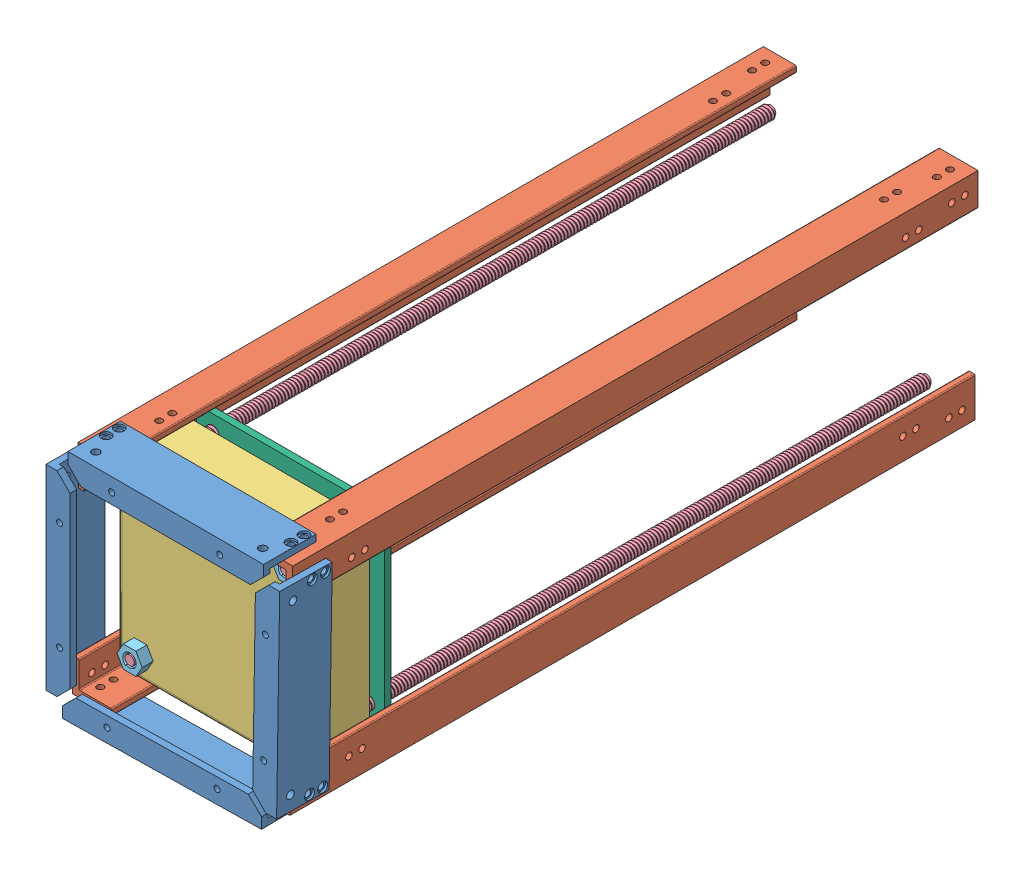
SolidWorks assembly RADIO2, configuration Default. Lengths in mm.
Overall size (103.88 103.99 324.84).
18 component instances, 6 part files, 26 mates.
Components (placement in the parent):
- Top Sipport-9: Top Sipport [Default] at (-70.7593 190.2338 9.9618) x (0 -0.999877 0.015674) z (0 -0.015674 -0.999877) size (89.4 11 24)
- Top Sipport-10: Top Sipport [Default] at (-113.8302 133.6631 11.3482) x (-0.999847 0 0.01749) z (-0.01749 0 -0.999847) size (89.4 11 24)
- Top Sipport-11: Top Sipport [Default] at (-170.4266 177.1068 12.2014) x (0 1 0) z (0 0 -1) size (89.4 11 24)
- Top Sipport-12: Top Sipport [Default] at (-127.1008 233.4379 9.4033) x (1 0 0) z (0 0 -1) size (89.4 11 24)
- Support-6: Support [Default] at (-166.8769 134.5557 -290.4415) x (1 0 0) z (0 1 0) size (18 313 15)
- Support-7: Support [Default] at (-169.6519 229.8882 -293.2396) x (0 -1 0) z (1 0 0) size (18 313 15)
- Support-8: Support [Default] at (-74.309 232.5453 -293.2396) x (-1 0 0) z (0 -1 0) size (18 313 15)
- Support-9: Support [Default] at (-71.6519 137.2129 -291.9167) x (0 1 0) z (-1 0 0) size (18 313 15)
- Top Plate2-2: Top Plate2 [Default] at (-98.3341 162.8515 -14.5967) x (0 -1 0) z (0 0 -1) size (92 92 23)
- Threaded Rod2-1: Threaded Rod2 [Default] at (-85.1519 148.0453 -302.5967) size (6.4 7.01 294.26)
- Nut-1: Nut [Default] at (-85.1519 148.0453 -14.5967) size (11.55 10 5.32)
- Nut-2: Nut [Default] at (-156.1519 219.0453 -14.5967) size (11.55 10 5.32)
- Nut-3: Nut [Default] at (-85.1519 219.0453 -14.5967) size (11.55 10 5.32)
- Nut-4: Nut [Default] at (-156.1519 148.0453 -14.5967) size (11.55 10 5.32)
- Threaded Rod2-2: Threaded Rod2 [Default] at (-156.1519 219.0453 -302.5967) size (6.4 7.01 294.26)
- Threaded Rod2-3: Threaded Rod2 [Default] at (-85.1519 219.0453 -302.5967) size (6.4 7.01 294.26)
- Threaded Rod2-4: Threaded Rod2 [Default] at (-156.1519 148.0453 -302.5967) size (6.4 7.01 294.26)
- Mid Plate-1: Mid Plate [Default] at (-150.0137 193.5688 -50.5967) size (86 86 3)
Mates (geometry in assembly coordinates):
- Coincident83: coincident: circle of Top Sipport-10; circle of Support-6
- Coincident84: coincident: circle of Top Sipport-11; circle of Support-6
- Coincident85: coincident: circle of Top Sipport-12; circle of Support-7
- Coincident87: coincident: circle of Top Sipport-12; circle of Support-7
- Coincident88: coincident: circle of Top Sipport-9; circle of Support-8
- Coincident89: coincident: circle of Top Sipport-12; circle of Support-8
- Coincident90: coincident: circle of Top Sipport-9; circle of Support-9
- Coincident91: coincident: circle of Top Sipport-10; circle of Support-9
- Coincident92: coincident: circle of Support-8; circle of Top Plate2-2
- Parallel9: parallel: line of Top Sipport-11 through (-169.2527 138.8376 -12.4981) axis (0 1 0); line of Top Plate2-2 through (-163.6519 141.5453 -37.5967) axis (0 1 0)
- Parallel10: parallel: line of Support-7 through (-169.6519 232.5453 -312.5967) axis (0 0 1); line of Top Plate2-2 through (-78.6519 140.5453 -37.5967) axis (0 0 1)
- Coincident95: coincident: circle of Top Plate2-2; circle of Nut-1
- Concentric10: concentric: circle of Top Plate2-2; circle of Threaded Rod2-1
- Coincident96: coincident: plane of Threaded Rod2-1 through (-85.1519 148.0453 -9.5967) normal (0 0 1); plane of Nut-1 through (-85.1519 148.0453 -9.5967) normal (0 0 1)
- Coincident97: coincident: circle of Top Plate2-2; circle of Nut-4
- Coincident98: coincident: circle of Top Plate2-2; circle of Nut-3
- Coincident99: coincident: circle of Top Plate2-2; circle of Nut-2
- Concentric11: concentric: circle of Top Plate2-2; circle of Threaded Rod2-2
- Coincident100: coincident: plane of Nut-2 through (-156.1519 219.0453 -9.5967) normal (0 0 1); plane of Threaded Rod2-2 through (-156.1519 219.0453 -9.5967) normal (0 0 1)
- Concentric12: concentric: circle of Top Plate2-2; circle of Threaded Rod2-3
- Coincident101: coincident: plane of Nut-3 through (-85.1519 219.0453 -9.5967) normal (0 0 1); plane of Threaded Rod2-3 through (-85.1519 219.0453 -9.5967) normal (0 0 1)
- Concentric13: concentric: circle of Top Plate2-2; circle of Threaded Rod2-4
- Coincident102: coincident: plane of Nut-4 through (-156.1519 148.0453 -9.5967) normal (0 0 1); plane of Threaded Rod2-4 through (-156.1519 148.0453 -9.5967) normal (0 0 1)
- Concentric15: concentric: circle of Threaded Rod2-1; circle of Mid Plate-1
- Concentric16: concentric: circle of Threaded Rod2-2; circle of Mid Plate-1
- Distance1: distance = 30 mm: plane of Mid Plate-1 through (-150.0137 193.5688 -47.5967) normal (0 0 1); plane of Top Plate2-2 through (-98.3341 162.8515 -17.5967) normal (0 0 -1)
